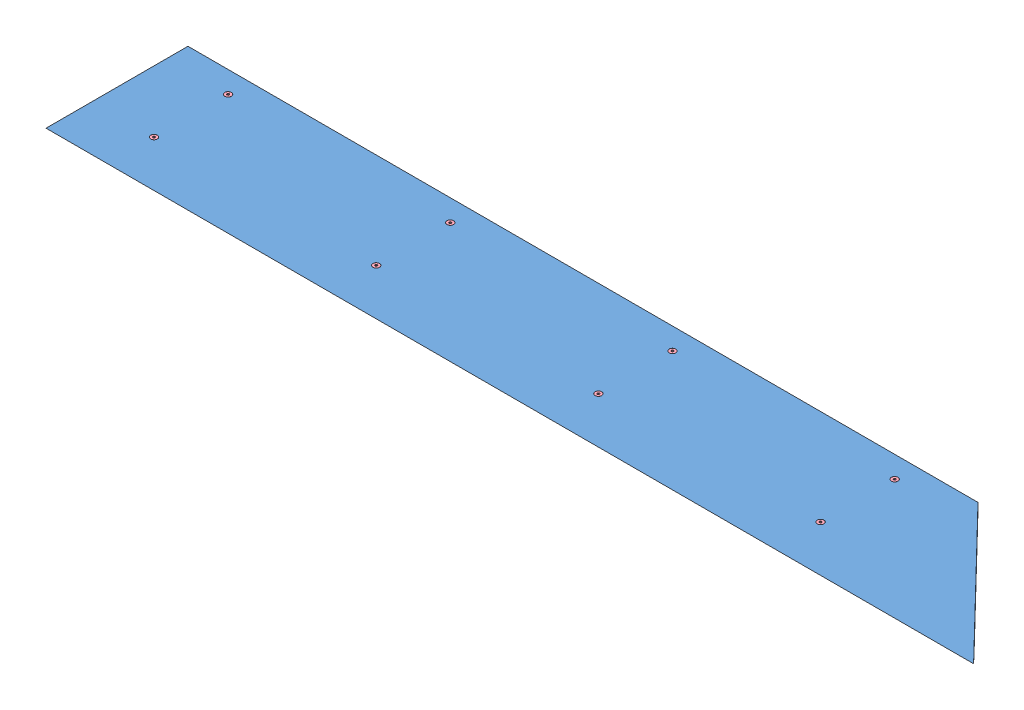
SolidWorks assembly GE-19053, configuration Default. Lengths in mm.
Overall size (1908.66 51.01 298.45).
21 component instances, 4 part files, 40 mates.
Components (placement in the parent):
- GE-19054-1: GE-19054 [Default] at (-11.9112 -4.3385 -141.1312) size (1908.66 12.7 292.1)
- GE-19055-1: GE-19055 [Default] at (-719.9362 -42.4385 -142.706) size (44.45 38.1 228.6)
- GE-19055-2: GE-19055 [Default] at (-262.7362 -42.4385 -142.706) size (44.45 38.1 228.6)
- GE-19055-3: GE-19055 [Default] at (194.4638 -42.4385 -142.706) size (44.45 38.1 228.6)
- GE-19055-4: GE-19055 [Default] at (651.6638 -42.4385 -142.706) size (44.45 38.1 228.6)
- nylock_.25_20-1: nylock_.25_20 [Default] at (673.8888 -9.1137 -96.6812) x (-1 0 0) z (0 0 1) size (11.11 7.94 12.83)
- nylock_.25_20-2: nylock_.25_20 [Default] at (673.8888 -9.1137 55.7188) x (-0.982082 0 0.188455) z (0.188455 0 0.982082) size (11.11 7.94 12.83)
- nylock_.25_20-3: nylock_.25_20 [Default] at (216.6888 -9.1137 -96.6812) x (-0.918365 0 0.395734) z (0.395734 0 0.918365) size (11.11 7.94 12.83)
- nylock_.25_20-4: nylock_.25_20 [Default] at (216.6888 -9.1137 55.7188) x (-0.8 0 0.6) z (0.6 0 0.8) size (11.11 7.94 12.83)
- nylock_.25_20-5: nylock_.25_20 [Default] at (-240.5112 -9.1137 -96.6812) x (-0.63358 0 0.773678) z (0.773678 0 0.63358) size (11.11 7.94 12.83)
- nylock_.25_20-6: nylock_.25_20 [Default] at (-240.5112 -9.1137 55.7188) x (-0.443629 0 0.896211) z (0.896211 0 0.443629) size (11.11 7.94 12.83)
- nylock_.25_20-7: nylock_.25_20 [Default] at (-697.7112 -9.1137 -96.6812) x (-0.263225 0 0.964735) z (0.964735 0 0.263225) size (11.11 7.94 12.83)
- nylock_.25_20-8: nylock_.25_20 [Default] at (-697.7112 -9.1137 55.7188) x (-0.120178 0 0.992752) z (0.992752 0 0.120178) size (11.11 7.94 12.83)
- flat_hex_.25_20_1-1: flat_hex_.25_20_1 [91253A542] at (673.8888 8.3615 -96.6812) x (1 0 0) z (0 1 0) size (13.49 13.49 25.61)
- flat_hex_.25_20_1-2: flat_hex_.25_20_1 [91253A542] at (673.8888 8.3615 55.7188) x (0.982082 0 -0.188455) z (0 1 0) size (13.49 13.49 25.61)
- flat_hex_.25_20_1-3: flat_hex_.25_20_1 [91253A542] at (216.6888 8.3615 -96.6812) x (0.918365 0 -0.395734) z (0 1 0) size (13.49 13.49 25.61)
- flat_hex_.25_20_1-4: flat_hex_.25_20_1 [91253A542] at (216.6888 8.3615 55.7188) x (0.8 0 -0.6) z (0 1 0) size (13.49 13.49 25.61)
- flat_hex_.25_20_1-5: flat_hex_.25_20_1 [91253A542] at (-240.5112 8.3615 55.7188) x (0.63358 0 -0.773678) z (0 1 0) size (13.49 13.49 25.61)
- flat_hex_.25_20_1-6: flat_hex_.25_20_1 [91253A542] at (-240.5112 8.3615 -96.6812) x (0.443629 0 -0.896211) z (0 1 0) size (13.49 13.49 25.61)
- flat_hex_.25_20_1-7: flat_hex_.25_20_1 [91253A542] at (-697.7112 8.3615 -96.6812) x (0.263225 0 -0.964735) z (0 1 0) size (13.49 13.49 25.61)
- flat_hex_.25_20_1-8: flat_hex_.25_20_1 [91253A542] at (-697.7112 8.3615 55.7188) x (0.120178 0 -0.992752) z (0 1 0) size (13.49 13.49 25.61)
Mates (geometry in assembly coordinates):
- Coincident1: coincident: plane of GE-19054-1 through (-11.9112 -4.3385 -141.1312) normal (0 -1 0); plane of GE-19055-1 through (-675.4862 -4.3385 81.1188) normal (0 1 0)
- Concentric1: concentric: cylinder of GE-19054-1 through (-697.7112 8.3615 -96.6812) axis (0 1 0) radius 3.5712; cylinder of GE-19055-1 through (-697.7112 -42.4385 -96.6812) axis (0 1 0) radius 3.3655
- Coincident2: coincident: plane of GE-19054-1 through (-11.9112 -4.3385 -141.1312) normal (0 -1 0); plane of GE-19055-2 through (-218.2862 -4.3385 81.1188) normal (0 1 0)
- Concentric2: concentric: cylinder of GE-19054-1 through (-240.5112 8.3615 -96.6812) axis (0 1 0) radius 3.5712; cylinder of GE-19055-2 through (-240.5112 -42.4385 -96.6812) axis (0 1 0) radius 3.3655
- Coincident3: coincident: plane of GE-19054-1 through (-11.9112 -4.3385 -141.1312) normal (0 -1 0); plane of GE-19055-3 through (238.9138 -4.3385 81.1188) normal (0 1 0)
- Concentric3: concentric: cylinder of GE-19054-1 through (216.6888 8.3615 -96.6812) axis (0 1 0) radius 3.5712; cylinder of GE-19055-3 through (216.6888 -42.4385 -96.6812) axis (0 1 0) radius 3.3655
- Coincident4: coincident: plane of GE-19054-1 through (-11.9112 -4.3385 -141.1312) normal (0 -1 0); plane of GE-19055-4 through (696.1138 -4.3385 81.1188) normal (0 1 0)
- Concentric4: concentric: cylinder of GE-19054-1 through (673.8888 8.3615 -96.6812) axis (0 1 0) radius 3.5712; cylinder of GE-19055-4 through (673.8888 -42.4385 -96.6812) axis (0 1 0) radius 3.3655
- Concentric5: concentric: cylinder of assembly; cylinder of assembly; cylinder of GE-19055-4 through (673.8888 -42.4385 -96.6812) axis (0 1 0) radius 3.3655; cylinder of nylock_.25_20-1 through (673.8888 -9.1137 -96.6812) axis (0 -1 0) radius 3.175
- Coincident5: coincident: plane of assembly; plane of assembly; plane of GE-19055-4 through (696.1138 -9.1137 -142.706) normal (0 -1 0); plane of nylock_.25_20-1 through (673.8888 -9.1137 -96.6812) normal (0 1 0)
- Concentric6: concentric: cylinder of assembly; cylinder of assembly; cylinder of GE-19055-4 through (673.8888 -42.4385 55.7188) axis (0 1 0) radius 3.3655; cylinder of nylock_.25_20-2 through (673.8888 -9.1137 55.7188) axis (0 -1 0) radius 3.175
- Coincident6: coincident: plane of assembly; plane of assembly; plane of GE-19055-4 through (696.1138 -9.1137 -142.706) normal (0 -1 0); plane of nylock_.25_20-2 through (673.8888 -9.1137 55.7188) normal (0 1 0)
- Coincident7: coincident: plane of assembly; plane of assembly; plane of GE-19055-4 through (696.1138 -9.1137 -142.706) normal (0 -1 0); plane of nylock_.25_20-3 through (216.6888 -9.1137 -96.6812) normal (0 1 0)
- Concentric7: concentric: cylinder of assembly; cylinder of assembly; cylinder of GE-19055-3 through (216.6888 -42.4385 -96.6812) axis (0 1 0) radius 3.3655; cylinder of nylock_.25_20-3 through (216.6888 -9.1137 -96.6812) axis (0 -1 0) radius 3.175
- Coincident8: coincident: plane of assembly; plane of assembly; plane of GE-19055-4 through (696.1138 -9.1137 -142.706) normal (0 -1 0); plane of nylock_.25_20-4 through (216.6888 -9.1137 55.7188) normal (0 1 0)
- Concentric8: concentric: cylinder of assembly; cylinder of assembly; cylinder of GE-19055-3 through (216.6888 -42.4385 55.7188) axis (0 1 0) radius 3.3655; cylinder of nylock_.25_20-4 through (216.6888 -9.1137 55.7188) axis (0 -1 0) radius 3.175
- Coincident9: coincident: plane of assembly; plane of assembly; plane of GE-19055-4 through (696.1138 -9.1137 -142.706) normal (0 -1 0); plane of nylock_.25_20-5 through (-240.5112 -9.1137 -96.6812) normal (0 1 0)
- Concentric9: concentric: cylinder of assembly; cylinder of assembly; cylinder of GE-19055-2 through (-240.5112 -42.4385 -96.6812) axis (0 1 0) radius 3.3655; cylinder of nylock_.25_20-5 through (-240.5112 -9.1137 -96.6812) axis (0 -1 0) radius 3.175
- Coincident10: coincident: plane of assembly; plane of assembly; plane of GE-19055-4 through (696.1138 -9.1137 -142.706) normal (0 -1 0); plane of nylock_.25_20-6 through (-240.5112 -9.1137 55.7188) normal (0 1 0)
- Concentric10: concentric: cylinder of assembly; cylinder of assembly; cylinder of GE-19055-2 through (-240.5112 -42.4385 55.7188) axis (0 1 0) radius 3.3655; cylinder of nylock_.25_20-6 through (-240.5112 -9.1137 55.7188) axis (0 -1 0) radius 3.175
- Coincident11: coincident: plane of assembly; plane of assembly; plane of GE-19055-4 through (696.1138 -9.1137 -142.706) normal (0 -1 0); plane of nylock_.25_20-7 through (-697.7112 -9.1137 -96.6812) normal (0 1 0)
- Concentric11: concentric: cylinder of assembly; cylinder of assembly; cylinder of GE-19055-1 through (-697.7112 -42.4385 -96.6812) axis (0 1 0) radius 3.3655; cylinder of nylock_.25_20-7 through (-697.7112 -9.1137 -96.6812) axis (0 -1 0) radius 3.175
- Coincident12: coincident: plane of assembly; plane of assembly; plane of GE-19055-4 through (696.1138 -9.1137 -142.706) normal (0 -1 0); plane of nylock_.25_20-8 through (-697.7112 -9.1137 55.7188) normal (0 1 0)
- Concentric12: concentric: cylinder of assembly; cylinder of assembly; cylinder of GE-19055-1 through (-697.7112 -42.4385 55.7188) axis (0 1 0) radius 3.3655; cylinder of nylock_.25_20-8 through (-697.7112 -9.1137 55.7188) axis (0 -1 0) radius 3.175
- Concentric13: concentric: cylinder of GE-19054-1 through (673.8888 8.3615 -96.6812) axis (0 1 0) radius 3.5712; cylinder of flat_hex_.25_20_1-1 through (673.8888 -17.0385 -96.6812) axis (0 -1 0) radius 3.175
- Coincident15: coincident: plane of GE-19054-1 through (-11.9112 8.3615 -141.1312) normal (0 1 0); plane of flat_hex_.25_20_1-1 through (673.8888 8.3615 -93.5062) normal (0 1 0)
- Coincident16: coincident: plane of GE-19054-1 through (-11.9112 8.3615 -141.1312) normal (0 1 0); plane of flat_hex_.25_20_1-2 through (674.4871 8.3615 58.8369) normal (0 1 0)
- Concentric14: concentric: cylinder of GE-19054-1 through (673.8888 8.3615 55.7188) axis (0 1 0) radius 3.5712; cylinder of flat_hex_.25_20_1-2 through (673.8888 -17.0385 55.7188) axis (0 -1 0) radius 3.175
- Coincident17: coincident: plane of GE-19054-1 through (-11.9112 8.3615 -141.1312) normal (0 1 0); plane of flat_hex_.25_20_1-3 through (217.9452 8.3615 -93.7654) normal (0 1 0)
- Concentric15: concentric: cylinder of GE-19054-1 through (216.6888 8.3615 -96.6812) axis (0 1 0) radius 3.5712; cylinder of flat_hex_.25_20_1-3 through (216.6888 -17.0385 -96.6812) axis (0 -1 0) radius 3.175
- Coincident18: coincident: plane of GE-19054-1 through (-11.9112 8.3615 -141.1312) normal (0 1 0); plane of flat_hex_.25_20_1-4 through (218.5938 8.3615 58.2588) normal (0 1 0)
- Concentric16: concentric: cylinder of GE-19054-1 through (216.6888 8.3615 55.7188) axis (0 1 0) radius 3.5712; cylinder of flat_hex_.25_20_1-4 through (216.6888 -17.0385 55.7188) axis (0 -1 0) radius 3.175
- Coincident19: coincident: plane of GE-19054-1 through (-11.9112 8.3615 -141.1312) normal (0 1 0); plane of flat_hex_.25_20_1-5 through (-238.0548 8.3615 57.7304) normal (0 1 0)
- Concentric17: concentric: cylinder of GE-19054-1 through (-240.5112 8.3615 55.7188) axis (0 1 0) radius 3.5712; cylinder of flat_hex_.25_20_1-5 through (-240.5112 -17.0385 55.7188) axis (0 -1 0) radius 3.175
- Coincident20: coincident: plane of GE-19054-1 through (-11.9112 8.3615 -141.1312) normal (0 1 0); plane of flat_hex_.25_20_1-6 through (-237.6658 8.3615 -95.2727) normal (0 1 0)
- Concentric18: concentric: cylinder of GE-19054-1 through (-240.5112 8.3615 -96.6812) axis (0 1 0) radius 3.5712; cylinder of flat_hex_.25_20_1-6 through (-240.5112 -17.0385 -96.6812) axis (0 -1 0) radius 3.175
- Coincident21: coincident: plane of GE-19054-1 through (-11.9112 8.3615 -141.1312) normal (0 1 0); plane of flat_hex_.25_20_1-7 through (-694.6482 8.3615 -95.8455) normal (0 1 0)
- Concentric19: concentric: cylinder of GE-19054-1 through (-697.7112 8.3615 -96.6812) axis (0 1 0) radius 3.5712; cylinder of flat_hex_.25_20_1-7 through (-697.7112 -17.0385 -96.6812) axis (0 -1 0) radius 3.175
- Coincident22: coincident: plane of GE-19054-1 through (-11.9112 8.3615 -141.1312) normal (0 1 0); plane of flat_hex_.25_20_1-8 through (-694.5592 8.3615 56.1003) normal (0 1 0)
- Concentric20: concentric: cylinder of GE-19054-1 through (-697.7112 8.3615 55.7188) axis (0 1 0) radius 3.5712; cylinder of flat_hex_.25_20_1-8 through (-697.7112 -17.0385 55.7188) axis (0 -1 0) radius 3.175
